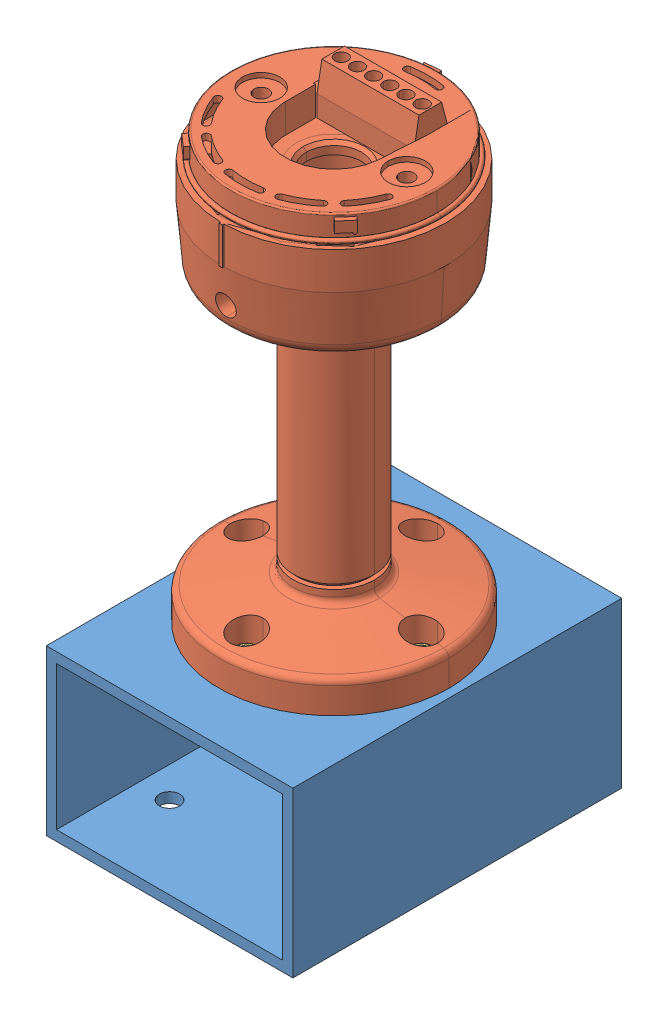
SolidWorks assembly GE-19106, configuration Default. Lengths in mm.
Overall size (86.66 195.48 101.6).
10 component instances, 4 part files, 20 mates.
Components (placement in the parent):
- GE-19105-1: GE-19105 [Default] at origin size (76.2 50.8 101.6)
- 855t-bpm10-1: 855t-bpm10 [Default] at (0.0002 119.4 50.8) size (86.66 146.21 88.63)
- round_hex_10_32_.625_full-14: round_hex_10_32_.625_full [91306A274] at (-27.0002 31.4654 50.8) x (1 0 0) z (0 1 0) size (9.17 9.17 18.62)
- nylock_10_32-1: nylock_10_32 [90631A411] at (-27.0002 22.225 50.8) x (-0.837169 0 -0.546944) z (-0.546944 0 0.837169) size (9.53 5.95 11)
- nylock_10_32-4: nylock_10_32 [90631A411] at (0 22.225 77.8002) x (-0.925243 0 -0.379375) z (-0.379375 0 0.925243) size (9.53 5.95 11)
- round_hex_10_32_.625_full-15: round_hex_10_32_.625_full [91306A274] at (0 31.4654 77.8002) x (0.982082 0 -0.188455) z (0 1 0) size (9.17 9.17 18.62)
- nylock_10_32-3: nylock_10_32 [90631A411] at (27.0002 22.225 50.8) x (-0.985271 0 -0.170998) z (-0.170998 0 0.985271) size (9.53 5.95 11)
- round_hex_10_32_.625_full-10: round_hex_10_32_.625_full [91306A274] at (27.0002 31.4654 50.8) x (0.918365 0 -0.395734) z (0 1 0) size (9.17 9.17 18.62)
- nylock_10_32-5: nylock_10_32 [90631A411] at (0 22.225 23.7998) x (-0.997902 0 0.064746) z (0.064746 0 0.997902) size (9.53 5.95 11)
- round_hex_10_32_.625_full-13: round_hex_10_32_.625_full [91306A274] at (0 31.4654 23.7998) x (0.8 0 -0.6) z (0 1 0) size (9.17 9.17 18.62)
Mates (geometry in assembly coordinates):
- Concentric1: concentric: cylinder of GE-19105-1 through (0 25.4 77.8002) axis (0 1 0) radius 2.5527; cylinder of 855t-bpm10-1 through (0.0002 25.4 77.8) axis (0 -1 0) radius 2.75
- Parallel1: parallel: cylinder of GE-19105-1 through (0 25.4 23.7998) axis (0 1 0) radius 2.5527; cylinder of 855t-bpm10-1 through (0.0002 25.4 23.8) axis (0 -1 0) radius 2.75
- Coincident2: coincident: plane of GE-19105-1 through (-38.1 25.4 101.6) normal (0 1 0); plane of 855t-bpm10-1 through (0.0002 25.4 50.8) normal (0 -1 0)
- Concentric5: concentric: cylinder of GE-19105-1 through (27.0002 25.4 50.8) axis (0 1 0) radius 2.5527; cylinder of 855t-bpm10-1 through (27.0002 25.4 50.8) axis (0 -1 0) radius 2.75
- Concentric9: concentric: cylinder of GE-19105-1 through (-27.0002 25.4 50.8) axis (0 1 0) radius 2.5527; cylinder of round_hex_10_32_.625_full-14 through (-27.0002 13.025 50.8) axis (0 -1 0) radius 2.413
- Coincident5: coincident: plane of assembly; plane of assembly; plane of 855t-bpm10-1 through (0.0002 28.9 50.8) normal (0 1 0); plane of round_hex_10_32_.625_full-14 through (-27.0002 28.9 55.3847) normal (0 -1 0)
- Concentric10: concentric: cylinder of assembly; cylinder of assembly; cylinder of round_hex_10_32_.625_full-14 through (-27.0002 13.025 50.8) axis (0 -1 0) radius 2.413; cylinder of nylock_10_32-1 through (-27.0002 17.1879 50.8) axis (0 1 0) radius 2.0454
- Coincident6: coincident: plane of GE-19105-1 through (-34.925 22.225 101.6) normal (0 -1 0); plane of nylock_10_32-1 through (-23.9924 22.225 46.1962) normal (0 1 0)
- Concentric11: concentric: cylinder of assembly; cylinder of assembly; cylinder of nylock_10_32-4 through (0 17.1879 77.8002) axis (0 1 0) radius 2.0454; cylinder of round_hex_10_32_.625_full-15 through (0 13.025 77.8002) axis (0 -1 0) radius 2.413
- Concentric12: concentric: cylinder of GE-19105-1 through (0 25.4 77.8002) axis (0 1 0) radius 2.5527; cylinder of round_hex_10_32_.625_full-15 through (0 13.025 77.8002) axis (0 -1 0) radius 2.413
- Coincident7: coincident: plane of assembly; plane of assembly; plane of 855t-bpm10-1 through (0.0002 28.9 50.8) normal (0 1 0); plane of round_hex_10_32_.625_full-15 through (0.864 28.9 82.3028) normal (0 -1 0)
- Coincident8: coincident: plane of GE-19105-1 through (-34.925 22.225 101.6) normal (0 -1 0); plane of nylock_10_32-4 through (2.0863 22.225 72.712) normal (0 1 0)
- Concentric13: concentric: cylinder of assembly; cylinder of assembly; cylinder of nylock_10_32-3 through (27.0002 17.1879 50.8) axis (0 1 0) radius 2.0454; cylinder of round_hex_10_32_.625_full-10 through (27.0002 13.025 50.8) axis (0 -1 0) radius 2.413
- Coincident9: coincident: plane of assembly; plane of assembly; plane of 855t-bpm10-1 through (0.0002 28.9 50.8) normal (0 1 0); plane of round_hex_10_32_.625_full-10 through (28.8145 28.9 55.0104) normal (0 -1 0)
- Coincident10: coincident: plane of GE-19105-1 through (-34.925 22.225 101.6) normal (0 -1 0); plane of nylock_10_32-3 through (27.9406 22.225 45.3817) normal (0 1 0)
- Concentric14: concentric: cylinder of GE-19105-1 through (27.0002 25.4 50.8) axis (0 1 0) radius 2.5527; cylinder of round_hex_10_32_.625_full-10 through (27.0002 13.025 50.8) axis (0 -1 0) radius 2.413
- Concentric15: concentric: cylinder of assembly; cylinder of assembly; cylinder of nylock_10_32-5 through (0 17.1879 23.7998) axis (0 1 0) radius 2.0454; cylinder of round_hex_10_32_.625_full-13 through (0 13.025 23.7998) axis (0 -1 0) radius 2.413
- Coincident11: coincident: plane of assembly; plane of assembly; plane of 855t-bpm10-1 through (0.0002 28.9 50.8) normal (0 1 0); plane of round_hex_10_32_.625_full-13 through (2.7508 28.9 27.4676) normal (0 -1 0)
- Coincident12: coincident: plane of GE-19105-1 through (-34.925 22.225 101.6) normal (0 -1 0); plane of nylock_10_32-5 through (-0.3561 22.225 18.3121) normal (0 1 0)
- Concentric16: concentric: cylinder of GE-19105-1 through (0 25.4 23.7998) axis (0 1 0) radius 2.5527; cylinder of round_hex_10_32_.625_full-13 through (0 13.025 23.7998) axis (0 -1 0) radius 2.413
